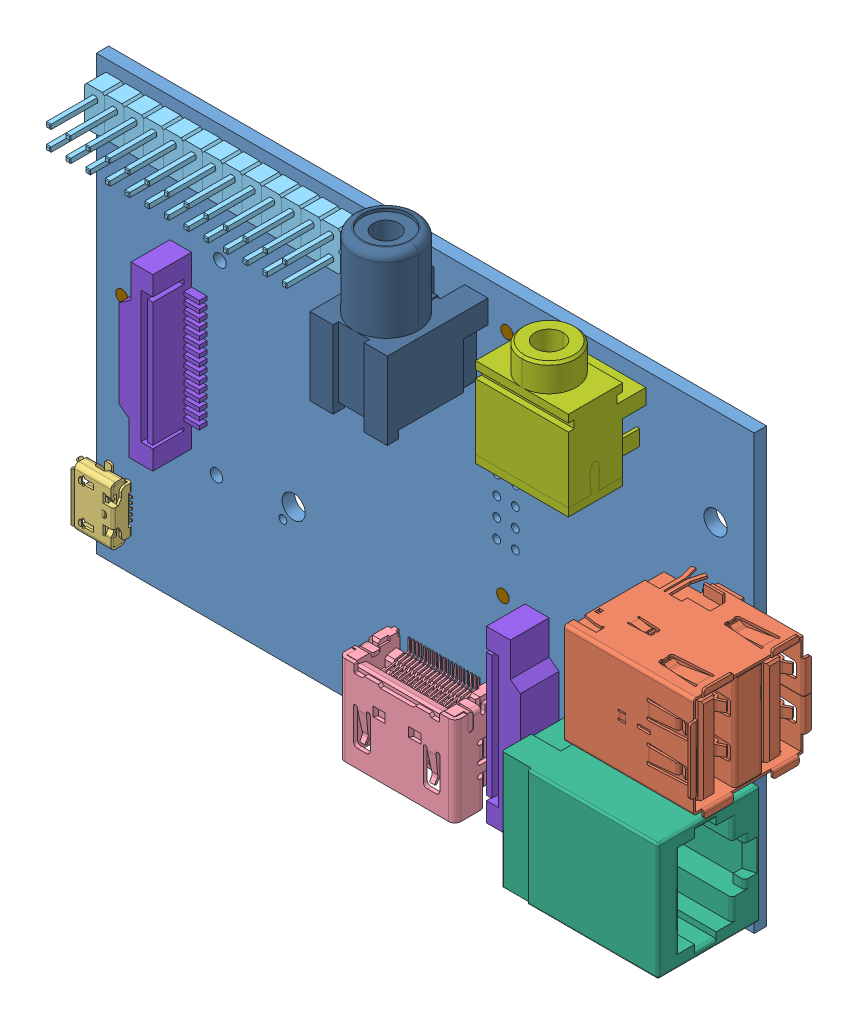
SolidWorks assembly RaspberryPi_B, configuration Default. Lengths in mm.
Overall size (93.19 64.44 19.65).
23 component instances, 10 part files, 0 mates.
Components (placement in the parent):
- RaspberryPi_PCB-1: RaspberryPi_PCB [Default] at origin size (85.01 56.01 1.61)
- 672982090_USB-1: 672982090_USB [Default] at (49.55 2.65 8.96) x (0 1 0) z (1 0 0) size (15.11 15.65 17.01)
- 473460001_microUSB-1: 473460001_microUSB [Default] at (-40.5 -20.65 2.825) x (0 -1 0) z (-1 0 0) size (7.99 2.95 5.44)
- 471510001_HDMI-1: 471510001_HDMI [Default] at (2.5 -29.032 5.005) x (1 0 0) z (0 -1 0) size (15.17 8.39 12.16)
- pin_strip-2-1: pin_strip-2 [Default] at (-40.23 22.69 4.3) size (2.55 5.09 11.61)
- pin_strip-2-2: pin_strip-2 [Default] at (-37.69 22.69 4.3) size (2.55 5.09 11.61)
- pin_strip-2-3: pin_strip-2 [Default] at (-35.15 22.69 4.3) size (2.55 5.09 11.61)
- pin_strip-2-4: pin_strip-2 [Default] at (-32.61 22.69 4.3) size (2.55 5.09 11.61)
- pin_strip-2-5: pin_strip-2 [Default] at (-30.07 22.69 4.3) size (2.55 5.09 11.61)
- pin_strip-2-6: pin_strip-2 [Default] at (-27.53 22.69 4.3) size (2.55 5.09 11.61)
- pin_strip-2-7: pin_strip-2 [Default] at (-24.99 22.69 4.3) size (2.55 5.09 11.61)
- pin_strip-2-8: pin_strip-2 [Default] at (-22.45 22.69 4.3) size (2.55 5.09 11.61)
- pin_strip-2-9: pin_strip-2 [Default] at (-19.91 22.69 4.3) size (2.55 5.09 11.61)
- pin_strip-2-10: pin_strip-2 [Default] at (-17.37 22.69 4.3) size (2.55 5.09 11.61)
- pin_strip-2-11: pin_strip-2 [Default] at (-14.83 22.69 4.3) size (2.55 5.09 11.61)
- pin_strip-2-12: pin_strip-2 [Default] at (-12.29 22.69 4.3) size (2.55 5.09 11.61)
- pin_strip-2-13: pin_strip-2 [Default] at (-9.75 22.69 4.3) size (2.55 5.09 11.61)
- c-5558065-1-a1-3d-1: c-5558065-1-a1-3d [Default] at (43.459 -18.4435 8.6358) x (0 1 0) z (1 0 0) size (15.12 16.95 20.58)
- SJ1-3555NG-1: SJ1-3555NG [Default] at (22.5 31.6 8.1) x (0 1 0) z (0 0 1) size (15.01 12.01 14.01)
- dsi_conn-1: dsi_conn [Default] at (-42.4962 -26.9954 1.6) size (6.39 22.01 5.01)
- dsi_conn-2: dsi_conn [Default] at (25.1985 10.9458 1.6) x (-1 0 0) z (0 0 1) size (6.39 22.01 5.01)
- raps-holes-1: raps-holes [Default] at (-42.5009 -28.0015 1.6) size (59.52 50.08 0.02)
- RCJ-044-1: RCJ-044 [Default] at (3.0996 15.9001 9.75) x (0 1 0) z (1 0 0) size (19.51 15.36 10.01)
